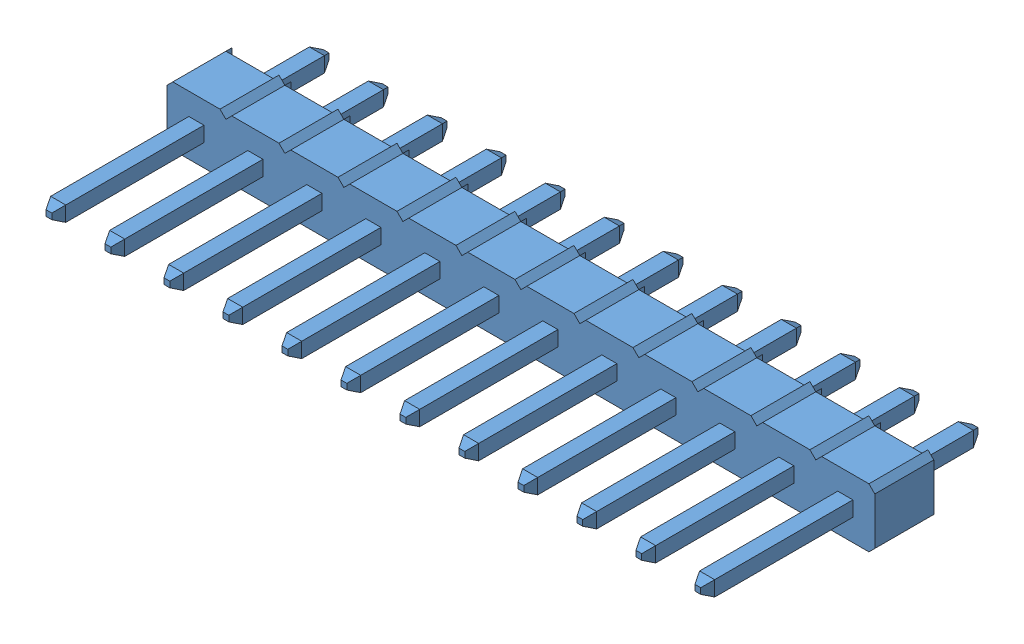
SolidWorks assembly 12pin_male, configuration Default. Lengths in mm.
Overall size (30.48 2.54 11.94).
2 component instances, 1 part files, 0 mates.
Components (placement in the parent):
- 12-Pin Header - Male - 2.54mm.step-1: 12-Pin Header - Male - 2.54mm.step [Default] at (-1.2832 20.4411 16.7031) size (30.48 2.54 11.94)
  - 12-Pin Header - Male - 2.54mm.step-1: 12-Pin Header - Male - 2.54mm.step [Default] x (1 0 0) z (0 -1 0) size (30.48 11.94 2.54)
